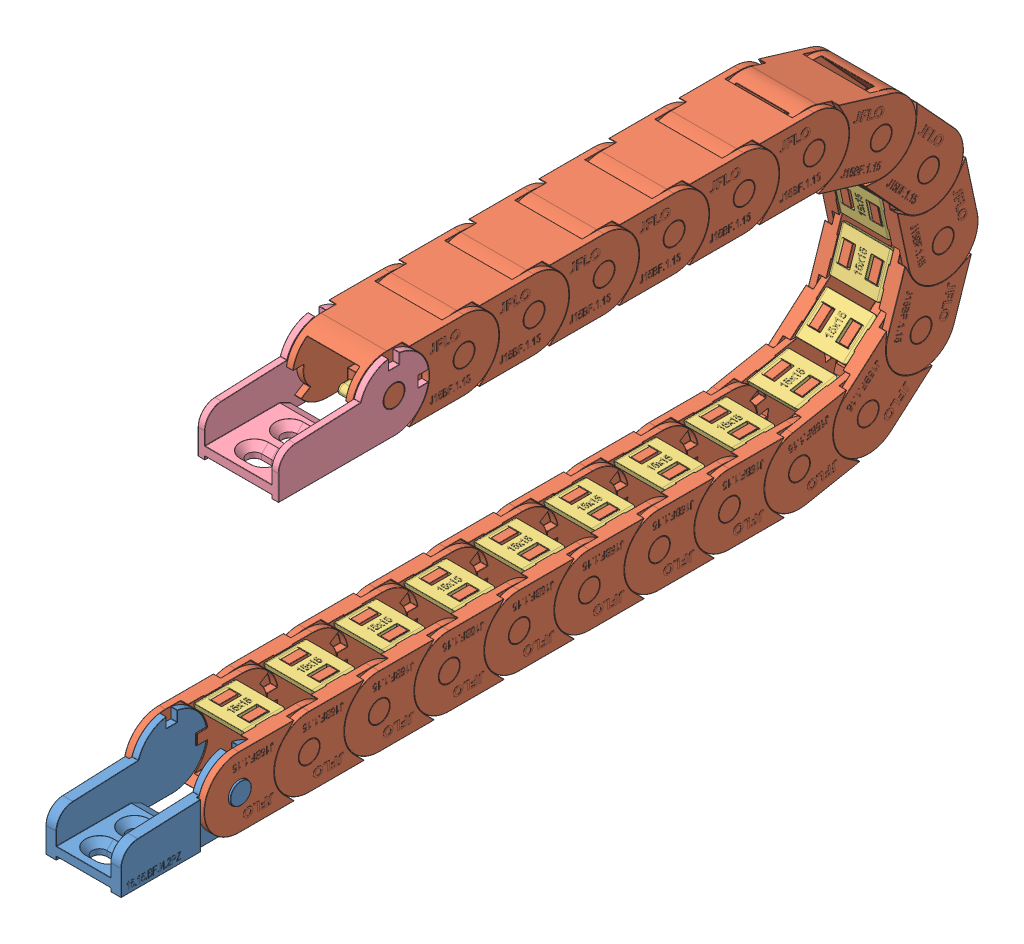
SolidWorks assembly J15BF.1.15. Chain, configuration Default. Lengths in mm.
Overall size (24 100.13 246.67).
63 component instances, 5 part files, 7 mates.
Components (placement in the parent):
- J15BF.1.15.2PZ-1: J15BF.1.15.2PZ [Default] at origin size (24 19.86 42.86)
- J15BF.1.Path-1: J15BF.1.Path [Default] at (0 0 256.8791) size (0 76 494.12) (hidden)
- J15BF.1.15. Closed Link-1: J15BF.1.15. Closed Link [Default] at (0 -10 -10) size (23.1 20.05 39.86)
  - J15BF.1.Link-1: J15BF.1.Link [J15BF.1.15] at origin size (23.1 20 39.86)
  - J15BF.1.Close-1: J15BF.1.Close [15x15] at (0 18 -1.5) size (15.15 2.09 12)
- J15BF.1.15. Closed Link-2: J15BF.1.15. Closed Link [Default] at (0 -10 -30) size (23.1 20.05 39.86)
  - J15BF.1.Link-1: J15BF.1.Link [J15BF.1.15] at origin size (23.1 20 39.86)
  - J15BF.1.Close-1: J15BF.1.Close [15x15] at (0 18 -1.5) size (15.15 2.09 12)
- J15BF.1.15. Closed Link-3: J15BF.1.15. Closed Link [Default] at (0 -10 -50) size (23.1 20.05 39.86)
  - J15BF.1.Link-1: J15BF.1.Link [J15BF.1.15] at origin size (23.1 20 39.86)
  - J15BF.1.Close-1: J15BF.1.Close [15x15] at (0 18 -1.5) size (15.15 2.09 12)
- J15BF.1.15. Closed Link-4: J15BF.1.15. Closed Link [Default] at (0 -10 -70) size (23.1 20.05 39.86)
  - J15BF.1.Link-1: J15BF.1.Link [J15BF.1.15] at origin size (23.1 20 39.86)
  - J15BF.1.Close-1: J15BF.1.Close [15x15] at (0 18 -1.5) size (15.15 2.09 12)
- J15BF.1.15. Closed Link-5: J15BF.1.15. Closed Link [Default] at (0 -10 -90) size (23.1 20.05 39.86)
  - J15BF.1.Link-1: J15BF.1.Link [J15BF.1.15] at origin size (23.1 20 39.86)
  - J15BF.1.Close-1: J15BF.1.Close [15x15] at (0 18 -1.5) size (15.15 2.09 12)
- J15BF.1.15. Closed Link-6: J15BF.1.15. Closed Link [Default] at (0 -10 -110) size (23.1 20.05 39.86)
  - J15BF.1.Link-1: J15BF.1.Link [J15BF.1.15] at origin size (23.1 20 39.86)
  - J15BF.1.Close-1: J15BF.1.Close [15x15] at (0 18 -1.5) size (15.15 2.09 12)
- J15BF.1.15. Closed Link-7: J15BF.1.15. Closed Link [Default] at (0 -10 -130) size (23.1 20.05 39.86)
  - J15BF.1.Link-1: J15BF.1.Link [J15BF.1.15] at origin size (23.1 20 39.86)
  - J15BF.1.Close-1: J15BF.1.Close [15x15] at (0 18 -1.5) size (15.15 2.09 12)
- J15BF.1.15. Closed Link-8: J15BF.1.15. Closed Link [Default] at (0 -10 -150) size (23.1 20.05 39.86)
  - J15BF.1.Link-1: J15BF.1.Link [J15BF.1.15] at origin size (23.1 20 39.86)
  - J15BF.1.Close-1: J15BF.1.Close [15x15] at (0 18 -1.5) size (15.15 2.09 12)
- J15BF.1.15. Closed Link-9: J15BF.1.15. Closed Link [Default] at (0 -7.9308 -171.7091) x (1 0 0) z (0 -0.188915 0.981993) size (23.1 20.05 39.86)
  - J15BF.1.Link-1: J15BF.1.Link [J15BF.1.15] at origin size (23.1 20 39.86)
  - J15BF.1.Close-1: J15BF.1.Close [15x15] at (0 18 -1.5) size (15.15 2.09 12)
- J15BF.1.15. Closed Link-10: J15BF.1.15. Closed Link [Default] at (0 2.7978 -193.748) x (1 0 0) z (0 -0.656379 0.754432) size (23.1 20.05 39.86)
  - J15BF.1.Link-1: J15BF.1.Link [J15BF.1.15] at origin size (23.1 20 39.86)
  - J15BF.1.Close-1: J15BF.1.Close [15x15] at (0 18 -1.5) size (15.15 2.09 12)
- J15BF.1.15. Closed Link-11: J15BF.1.15. Closed Link [Default] at (0 23.2247 -207.3804) x (1 0 0) z (0 -0.948541 0.316654) size (23.1 20.05 39.86)
  - J15BF.1.Link-1: J15BF.1.Link [J15BF.1.15] at origin size (23.1 20 39.86)
  - J15BF.1.Close-1: J15BF.1.Close [15x15] at (0 18 -1.5) size (15.15 2.09 12)
- J15BF.1.15. Closed Link-12: J15BF.1.15. Closed Link [Default] at (0 47.7446 -208.7527) x (1 0 0) z (0 -0.97795 -0.20884) size (23.1 20.05 39.86)
  - J15BF.1.Link-1: J15BF.1.Link [J15BF.1.15] at origin size (23.1 20 39.86)
  - J15BF.1.Close-1: J15BF.1.Close [15x15] at (0 18 -1.5) size (15.15 2.09 12)
- J15BF.1.15. Closed Link-13: J15BF.1.15. Closed Link [Default] at (0 69.5651 -197.4845) x (1 0 0) z (0 -0.736458 -0.676483) size (23.1 20.05 39.86)
  - J15BF.1.Link-1: J15BF.1.Link [J15BF.1.15] at origin size (23.1 20 39.86)
  - J15BF.1.Close-1: J15BF.1.Close [15x15] at (0 18 -1.5) size (15.15 2.09 12)
- J15BF.1.15. Closed Link-14: J15BF.1.15. Closed Link [Default] at (0 82.6418 -176.6974) x (1 0 0) z (0 -0.290962 -0.956735) size (23.1 20.05 39.86)
  - J15BF.1.Link-1: J15BF.1.Link [J15BF.1.15] at origin size (23.1 20 39.86)
  - J15BF.1.Close-1: J15BF.1.Close [15x15] at (0 18 -1.5) size (15.15 2.09 12)
- J15BF.1.15. Closed Link-15: J15BF.1.15. Closed Link [Default] at (0 85.992 -154.2284) x (1 0 0) z (0 -0.000795 -1) size (23.1 20.05 39.86)
  - J15BF.1.Link-1: J15BF.1.Link [J15BF.1.15] at origin size (23.1 20 39.86)
  - J15BF.1.Close-1: J15BF.1.Close [15x15] at (0 18 -1.5) size (15.15 2.09 12)
- J15BF.1.15. Closed Link-16: J15BF.1.15. Closed Link [Default] at (0 86 -134.2204) x (1 0 0) z (0 0 -1) size (23.1 20.05 39.86)
  - J15BF.1.Link-1: J15BF.1.Link [J15BF.1.15] at origin size (23.1 20 39.86)
  - J15BF.1.Close-1: J15BF.1.Close [15x15] at (0 18 -1.5) size (15.15 2.09 12)
- J15BF.1.15. Closed Link-17: J15BF.1.15. Closed Link [Default] at (0 86 -114.2204) x (1 0 0) z (0 0 -1) size (23.1 20.05 39.86)
  - J15BF.1.Link-1: J15BF.1.Link [J15BF.1.15] at origin size (23.1 20 39.86)
  - J15BF.1.Close-1: J15BF.1.Close [15x15] at (0 18 -1.5) size (15.15 2.09 12)
- J15BF.1.15. Closed Link-18: J15BF.1.15. Closed Link [Default] at (0 86 -94.2204) x (1 0 0) z (0 0 -1) size (23.1 20.05 39.86)
  - J15BF.1.Link-1: J15BF.1.Link [J15BF.1.15] at origin size (23.1 20 39.86)
  - J15BF.1.Close-1: J15BF.1.Close [15x15] at (0 18 -1.5) size (15.15 2.09 12)
- J15BF.1.15. Closed Link-19: J15BF.1.15. Closed Link [Default] at (0 86 -74.2204) x (1 0 0) z (0 0 -1) size (23.1 20.05 39.86)
  - J15BF.1.Link-1: J15BF.1.Link [J15BF.1.15] at origin size (23.1 20 39.86)
  - J15BF.1.Close-1: J15BF.1.Close [15x15] at (0 18 -1.5) size (15.15 2.09 12)
- J15BF.1.15. Closed Link-20: J15BF.1.15. Closed Link [Default] at (0 86 -54.2204) x (1 0 0) z (0 0 -1) size (23.1 20.05 39.86)
  - J15BF.1.Link-1: J15BF.1.Link [J15BF.1.15] at origin size (23.1 20 39.86)
  - J15BF.1.Close-1: J15BF.1.Close [15x15] at (0 18 -1.5) size (15.15 2.09 12)
- J15BF.1.15.1PZ-1: J15BF.1.15.1PZ [Default] at (0 76 -44.2204) size (23.05 19.86 42.86)
Mates (geometry in assembly coordinates):
- Coincident1: coincident aligned: plane of J15BF.1.15.2PZ-1 through (0 0 0) normal (1 0 0); plane of J15BF.1.Path-1 through (0 0 256.8791) normal (1 0 0)
- Coincident2: coincident aligned: plane of J15BF.1.15.2PZ-1 through (0 0 0) normal (0 1 0); plane of J15BF.1.Path-1 through (0 0 256.8791) normal (0 1 0)
- Concentric1: concentric anti-aligned: cylinder of J15BF.1.15.2PZ-1 through (12 0 0) axis (-1 0 0) radius 3; cylinder of J15BF.1.15. Closed Link-1/J15BF.1.Link-1 through (-11.5 0 0) axis (1 0 0) radius 3.05
- Concentric2: concentric aligned: cylinder of J15BF.1.15. Closed Link-20/J15BF.1.Link-1 through (9.45 76 -44.2204) axis (1 0 0) radius 3; cylinder of J15BF.1.15.1PZ-1 through (-11.5 76 -44.2204) axis (1 0 0) radius 3.05
- Parallel1: parallel aligned: plane of J15BF.1.15.2PZ-1 through (0 0 0) normal (0 1 0); plane of J15BF.1.15.1PZ-1 through (0 76 -44.2204) normal (0 1 0)
- Coincident3: coincident aligned: plane of J15BF.1.15.2PZ-1 through (0 0 0) normal (1 0 0); plane of J15BF.1.15.1PZ-1 through (0 76 -44.2204) normal (1 0 0)
- LimitAngle1: limit planar angle = 0 rad aligned: plane of J15BF.1.15.1PZ-1 through (-11.5 82.9 -45.7704) normal (0 1 0); plane of J15BF.1.15. Closed Link-20/J15BF.1.Link-1 through (-11.5 86 -74.2204) normal (0 1 0)
